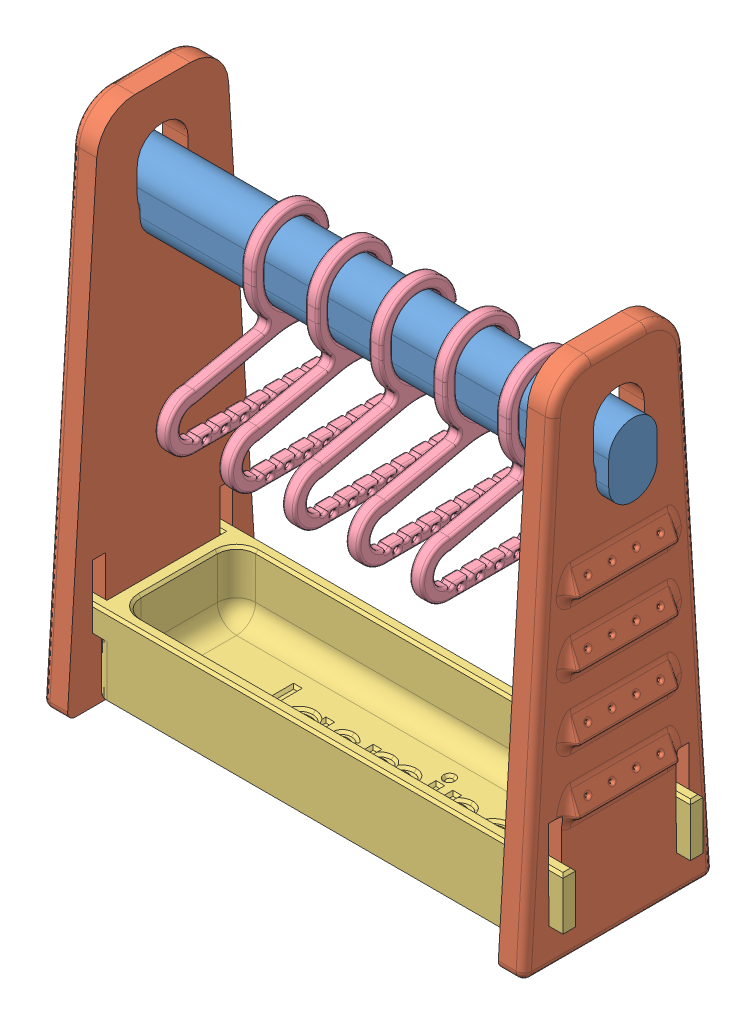
SolidWorks assembly rack_assem, configuration Default. Lengths in mm.
Overall size (200.09 200 96.73).
9 component instances, 4 part files, 0 mates.
Components (placement in the parent):
- rod-1: rod [Default] at origin size (200 28.5 19)
- side_support-2: side_support [Default] at (15.4704 -67.3482 0.0803) x (0 0 -1) z (1 0 0) size (74.61 200 13.84)
- side_support-4: side_support [Default] at (184.5296 -67.3482 0.0803) x (0 0 1) z (-1 0 0) size (74.61 200 13.84)
- tray-1: tray [Default] at (100.0853 -162.2379 2.5789) size (200 30 55)
- hanger-1: hanger [Default] at (161.4037 -5.5327 0.1284) x (0 0 -1) z (1 0 0) size (96.73 65.02 5.14)
- hanger-2: hanger [Default] at (136.4037 -5.5327 0.1284) x (0 0 -1) z (1 0 0) size (96.73 65.02 5.14)
- hanger-3: hanger [Default] at (111.4037 -5.5327 0.1284) x (0 0 -1) z (1 0 0) size (96.73 65.02 5.14)
- hanger-4: hanger [Default] at (86.4037 -5.5327 0.1284) x (0 0 -1) z (1 0 0) size (96.73 65.02 5.14)
- hanger-5: hanger [Default] at (61.4037 -5.5327 0.1284) x (0 0 -1) z (1 0 0) size (96.73 65.02 5.14)
